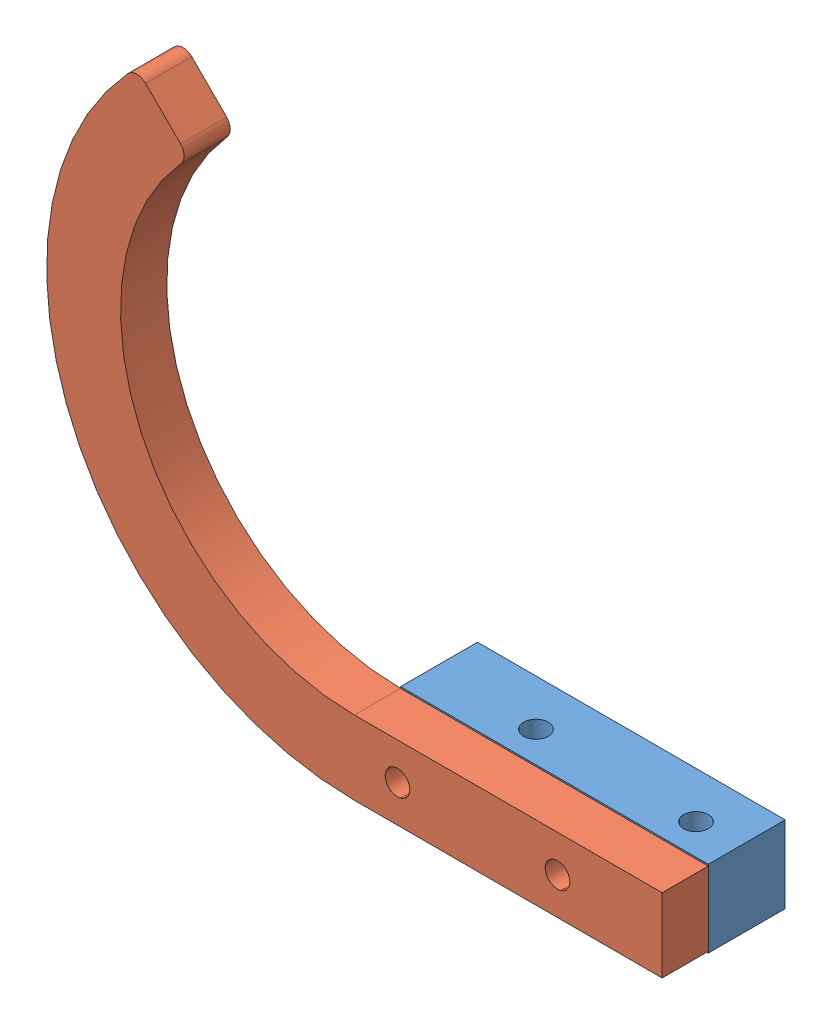
SolidWorks assembly MS-A-0017-Thruster Guard Assembly, Left, configuration Default. Lengths in mm.
Overall size (127 107.63 25.4).
4 component instances, 3 part files, 10 mates.
Components (placement in the parent):
- MS-P-0012-Thruster, Horizontal Attachment Block-1: MS-P-0012-Thruster, Horizontal Attachment Block [Default] at (24.4741 23.6152 49.4978) x (1 0 0) z (0 0 -1) size (63.5 15.88 15.88)
- MS-P-0011-Thruster, Horizontal Guard-1: MS-P-0011-Thruster, Horizontal Guard [Default] at (-7.2759 87.4327 57.4353) size (127 107.31 9.53)
- SHCS-3: SHCS [1, .25-20] at (34.6341 31.5527 54.2603) x (0 0 1) z (-0.979412 -0.201871 0) (suppressed, hidden)
- SHCS-4: SHCS [1, .25-20] at (1.6141 31.5527 54.2603) x (0 0 1) z (-1 0 0) (suppressed, hidden)
Mates (geometry in assembly coordinates):
- Coincident1: coincident anti-aligned: plane of MS-P-0012-Thruster, Horizontal Attachment Block-1 through (-7.2759 39.4902 57.4353) normal (0 0 1); plane of MS-P-0011-Thruster, Horizontal Guard-1 through (-52.1397 128.7045 57.4353) normal (0 0 -1)
- Concentric1: concentric anti-aligned: cylinder of MS-P-0012-Thruster, Horizontal Attachment Block-1 through (1.6141 31.5527 41.5603) axis (0 0 -1) radius 3.2639; cylinder of MS-P-0011-Thruster, Horizontal Guard-1 through (1.6141 31.5527 66.9603) axis (0 0 1) radius 2.5527
- Concentric2: concentric anti-aligned: cylinder of MS-P-0012-Thruster, Horizontal Attachment Block-1 through (34.6341 31.5527 41.5603) axis (0 0 -1) radius 3.2639; cylinder of MS-P-0011-Thruster, Horizontal Guard-1 through (34.6341 31.5527 66.9603) axis (0 0 1) radius 2.5527
- Coincident21: coincident anti-aligned: plane of MS-P-0012-Thruster, Horizontal Attachment Block-1 through (24.4741 39.4902 49.4978) normal (0 1 0); plane of SHCS-1 through (-14.2875 39.4902 0) normal (0 -1 0)
- Concentric5: concentric: cylinder of MS-P-0011-Thruster, Horizontal Guard-1 through (1.6141 31.5527 66.9603) axis (0 0 1) radius 2.5527; cylinder of SHCS-2 through (1.6141 31.5527 41.5603) axis (0 0 1) radius 3.175
- Coincident3: coincident anti-aligned: plane of MS-P-0012-Thruster, Horizontal Attachment Block-1 through (-7.2759 39.4902 41.5603) normal (0 0 -1); plane of SHCS-2 through (1.6141 35.9977 41.5603) normal (0 0 1)
- Concentric6: concentric aligned: cylinder of MS-P-0011-Thruster, Horizontal Guard-1 through (34.6341 31.5527 66.9603) axis (0 0 1) radius 2.5527; cylinder of SHCS-3 through (34.6341 31.5527 41.5603) axis (0 0 1) radius 3.175
- Coincident4: coincident anti-aligned: plane of MS-P-0012-Thruster, Horizontal Attachment Block-1 through (-7.2759 39.4902 41.5603) normal (0 0 -1); plane of SHCS-3 through (33.7368 35.9062 41.5603) normal (0 0 1)
- Concentric7: concentric aligned: cylinder of MS-P-0011-Thruster, Horizontal Guard-1 through (1.6141 31.5527 66.9603) axis (0 0 1) radius 2.5527; cylinder of SHCS-4 through (1.6141 31.5527 41.5603) axis (0 0 1) radius 3.175
- Coincident5: coincident anti-aligned: plane of MS-P-0012-Thruster, Horizontal Attachment Block-1 through (-7.2759 39.4902 41.5603) normal (0 0 -1); plane of SHCS-4 through (1.6141 35.9977 41.5603) normal (0 0 1)
